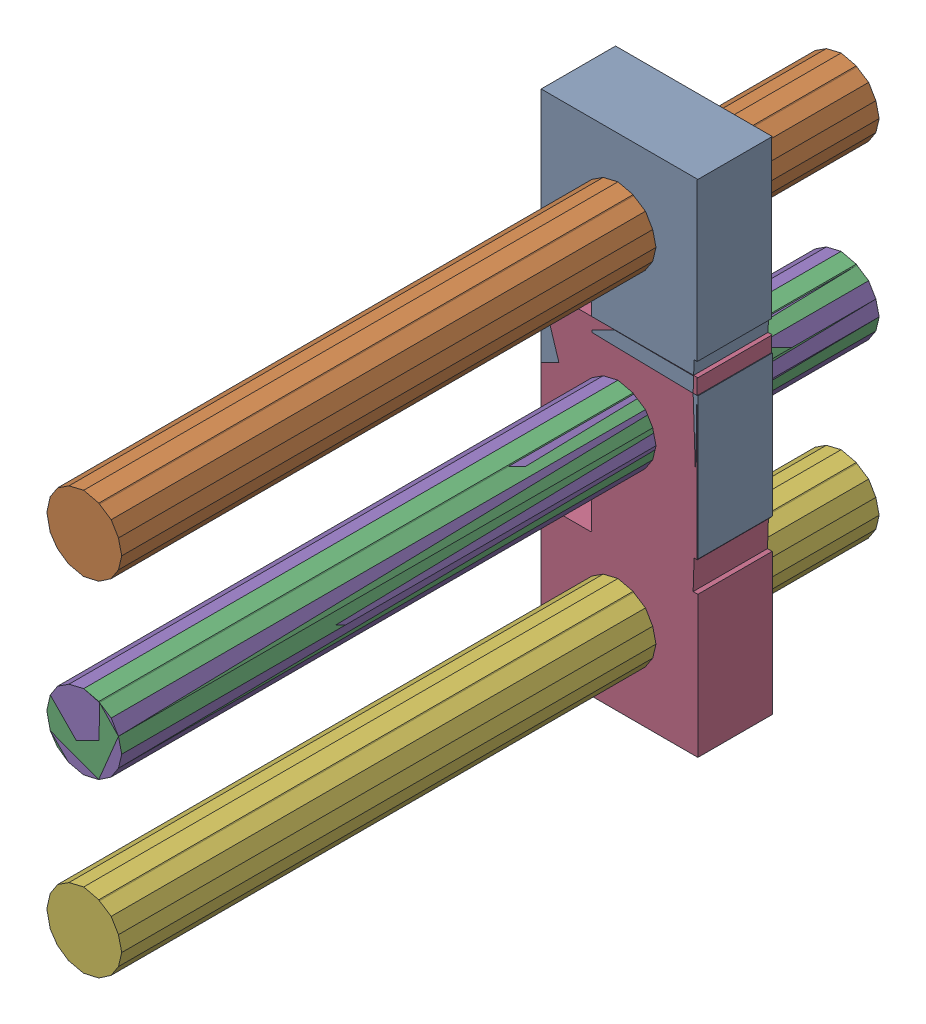
SolidWorks assembly H2, configuration Default. Lengths in mm.
Overall size (2.33 7.4 11.2).
12 component instances, 2 part files, 0 mates.
Components (placement in the parent):
- 432124432-1: 432124432 [Default] at (25.2046 26.9583 0) size (2.33 4.86 1.1)
  - Extruded (9)-1: Extruded (9) [Default] at origin size (2.33 4.86 1.1)
- 432124176-1: 432124176 [Default] at (25.195 28.2152 -2.2) size (1.11 1.11 11.2)
  - Extruded (10)-1: Extruded (10) [Default] at origin size (1.11 1.11 11.2)
- 432124176_1-1: 432124176_1 [Default] at (25.195 25.6752 -2.2) size (1.11 1.11 11.2)
  - Extruded (10)-1: Extruded (10) [Default] at origin size (1.11 1.11 11.2)
- 432124432_1-1: 432124432_1 [Default] at (25.2046 24.4183 0) size (2.33 4.86 1.1)
  - Extruded (9)-1: Extruded (9) [Default] at origin size (2.33 4.86 1.1)
- 432124176_2-1: 432124176_2 [Default] at (25.195 25.6752 -2.2) size (1.11 1.11 11.2)
  - Extruded (10)-1: Extruded (10) [Default] at origin size (1.11 1.11 11.2)
- 432124176_3-1: 432124176_3 [Default] at (25.195 23.1352 -2.2) size (1.11 1.11 11.2)
  - Extruded (10)-1: Extruded (10) [Default] at origin size (1.11 1.11 11.2)
